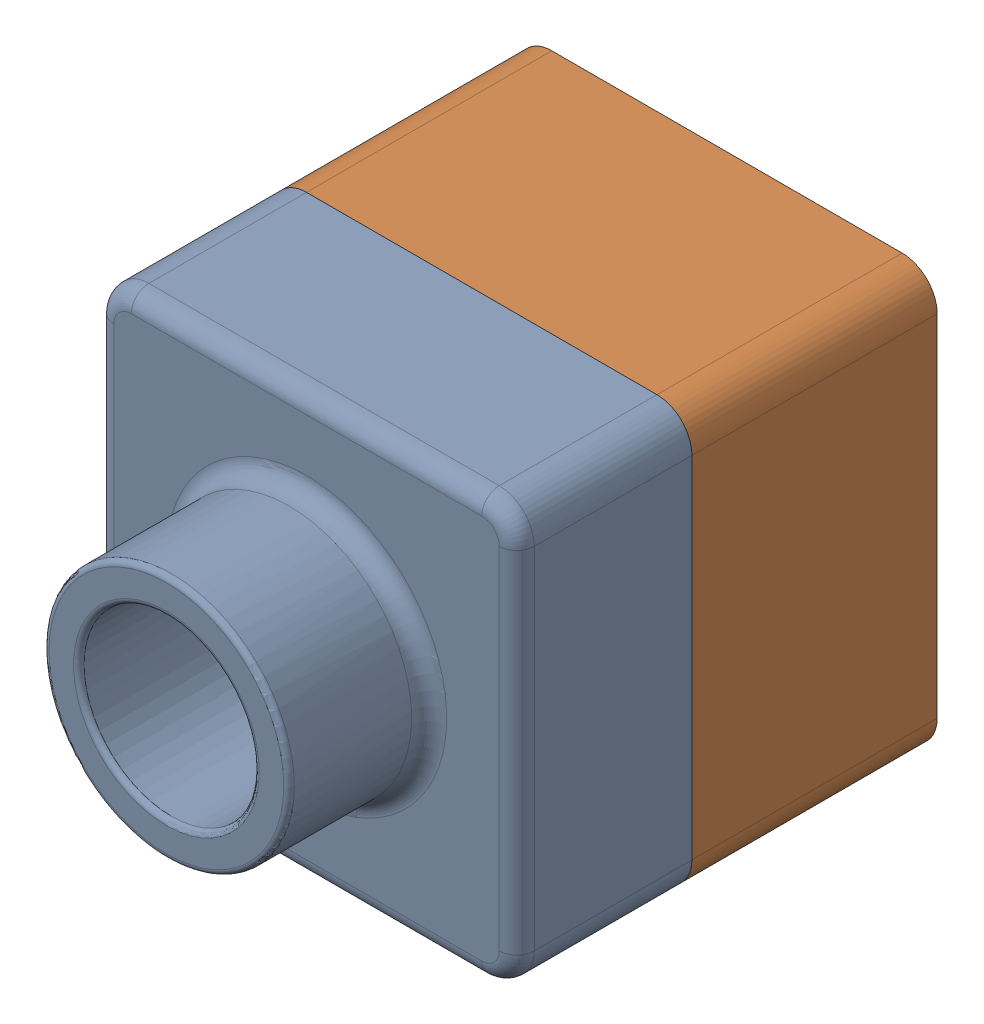
SolidWorks assembly tutor, configuration Default. Lengths in mm.
Overall size (120 120 160).
2 component instances, 2 part files, 3 mates.
Components (placement in the parent):
- Tutor1-1: Tutor1 [Default] at (-66.6147 -28.9929 54.849) size (120 120 90)
- Tutor2-2: Tutor2 [Default] at (-66.6147 -28.9929 -15.151) size (120 120 90)
Mates (geometry in assembly coordinates):
- Coincident4: coincident aligned: line of Tutor1-1 through (43.3853 91.0071 54.849) axis (-1 0 0); line of Tutor2-2 through (43.3853 91.0071 54.849) axis (-1 0 0)
- Coincident5: coincident aligned: plane of Tutor1-1 through (53.3853 -28.9929 104.849) normal (1 0 0); plane of Tutor2-2 through (53.3853 -28.9929 74.849) normal (1 0 0)
- Coincident6: coincident aligned: plane of Tutor1-1 through (-66.6147 91.0071 104.849) normal (0 1 0); plane of Tutor2-2 through (-66.6147 91.0071 74.849) normal (0 1 0)
